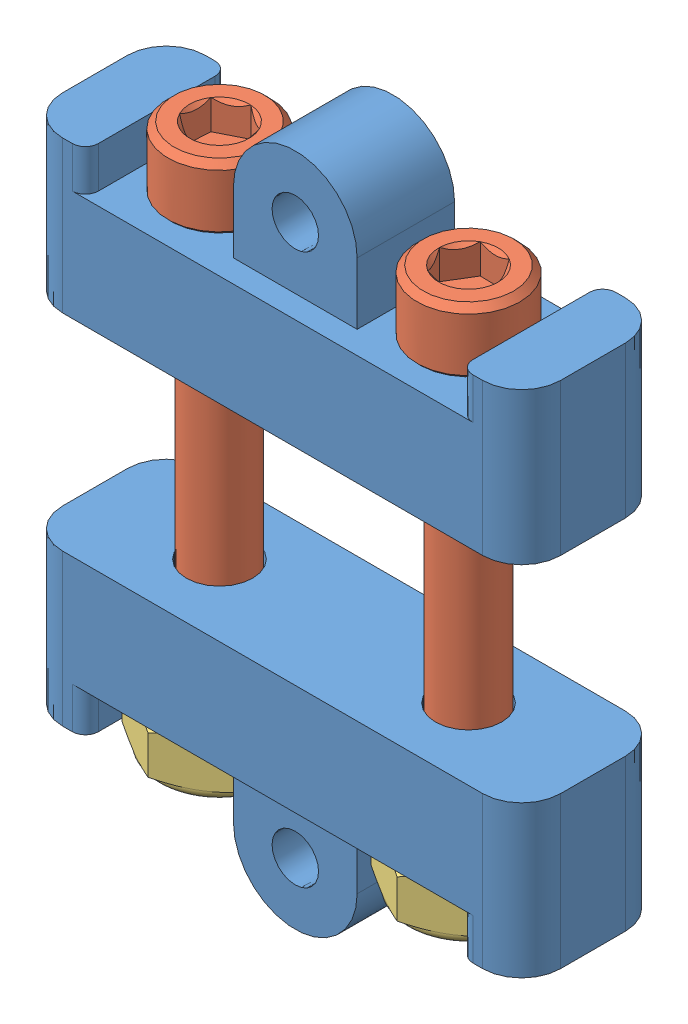
SolidWorks assembly WCP-0052 Chain Tensioner, configuration Default. Lengths in mm.
Overall size (38.35 51.92 13.75).
6 component instances, 3 part files, 0 mates.
Components (placement in the parent):
- WCP-0052-001 Rev1-1: WCP-0052-001 Rev1 [Default] at origin size (38.35 18.02 11)
- WCP-0052-001 Rev1-2: WCP-0052-001 Rev1 [Default] at (0 -32.875 0) x (1 0 0) z (0 0 -1) size (38.35 18.02 11)
- 90044A118_SHCS_#10-32_1_500L_Default_As Machined_-1: 90044A118_SHCS_#10-32_1_500L_Default_As Machined_ [Default] at (9.5885 -19.05 0) x (0 -1 0) z (-0.854878 0 -0.51883) size (43.15 7.92 7.92)
- 90044A118_SHCS_#10-32_1_500L_Default_As Machined_-2: 90044A118_SHCS_#10-32_1_500L_Default_As Machined_ [Default] at (-9.5885 -19.05 0) x (0 -1 0) z (0.449734 0 0.893163) size (43.15 7.92 7.92)
- 90633A411_#10-32_thin_locknut_90633A411-1: 90633A411_#10-32_thin_locknut_90633A411 [Default] at (9.5885 -32.875 0) x (0.5 0 -0.866025) z (-0.866025 0 -0.5) size (9.53 4.55 11)
- 90633A411_#10-32_thin_locknut_90633A411-2: 90633A411_#10-32_thin_locknut_90633A411 [Default] at (-9.5885 -32.875 0) x (1 0 0) z (0 0 -1) size (9.53 4.55 11)
